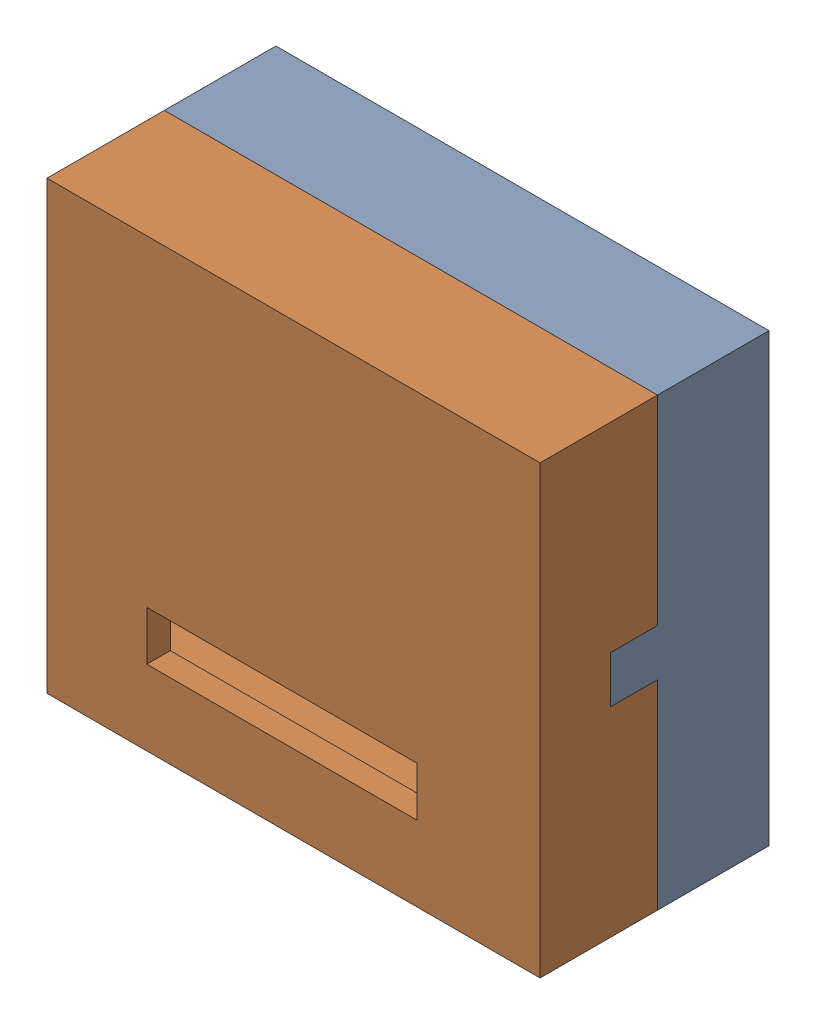
SolidWorks assembly 子设备, configuration 默认. Lengths in mm.
Overall size (42 38 19.5).
2 component instances, 2 part files, 3 mates.
Components (placement in the parent):
- 零件1-1: 零件1 [默认] at (-24.4534 -11.5186 -0.75) size (42 38 13.5)
- 标准壳2-1: 标准壳2 [默认] at (-20.9534 22.9814 12.75) x (1 0 0) z (0 0 -1) size (42 38 10)
Mates (geometry in assembly coordinates):
- 重合1: coincident: line of 零件1-1 through (-24.4534 9.4814 6.75) axis (0 -1 0); line of 标准壳2-1 through (-24.4534 5.4814 6.75) axis (0 1 0)
- 重合2: coincident: plane of 零件1-1 through (-24.4534 -11.5186 6.75) normal (0 0 1); plane of 标准壳2-1 through (-20.9534 22.9814 6.75) normal (0 0 -1)
- 重合3: coincident anti-aligned: plane of 零件1-1 through (-24.4534 5.4814 6.75) normal (0 -1 0); plane of 标准壳2-1 through (-20.9534 5.4814 6.75) normal (0 1 0)
